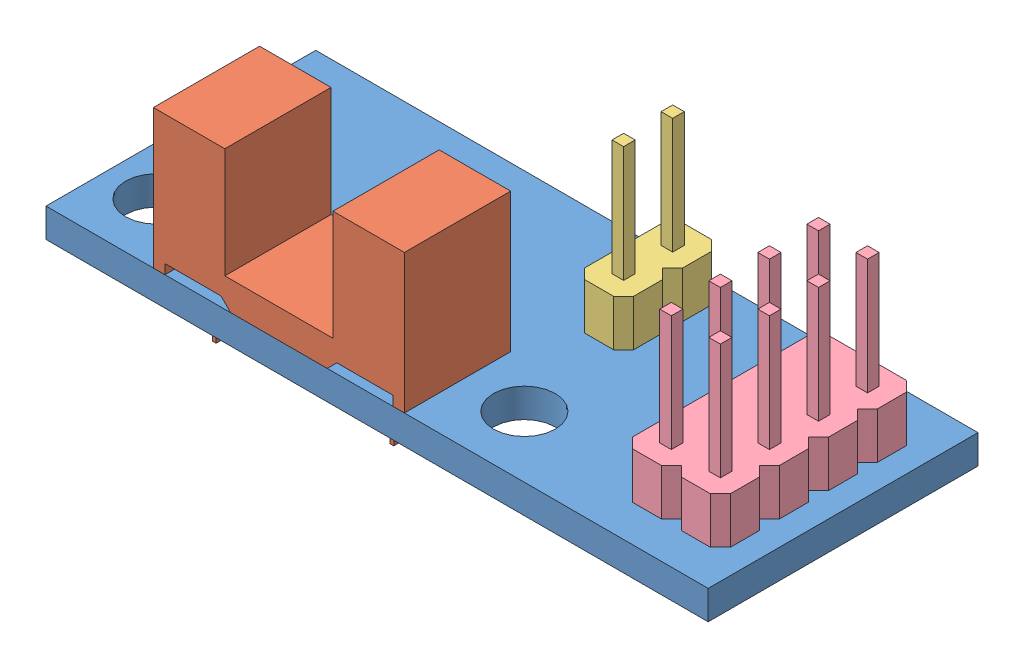
SolidWorks assembly Optoswitch board assy, configuration По умолчанию. Lengths in mm.
Overall size (34.29 11.5 13.97).
4 component instances, 4 part files, 11 mates.
Components (placement in the parent):
- Optoswitch board-1: Optoswitch board [По умолчанию] at (-0.4597 -1.5873 0) size (34.29 1.5 13.97)
- optoswitch-1: optoswitch [По умолчанию] at (-5.5447 -0.0873 1.485) size (13 10.2 5.5)
- Pin header - 2 pin-1: Pin header - 2 pin [По умолчанию] at (2.7853 -0.0873 -5.075) x (0 0 1) z (-1 0 0) size (5.08 11.5 2.54)
- Pin header - 8 pin-1: Pin header - 8 pin [По умолчанию] at (12.8753 -0.0873 0.005) x (1 0 0) z (0 1 0) size (5.08 10.16 11.5)
Mates (geometry in assembly coordinates):
- Совпадение1: coincident aligned: plane of Pin header - 2 pin-1 through (2.7853 -0.0873 -8.3641) normal (0 -1 0); plane of Pin header - 8 pin-1 through (12.8753 -0.0873 8.9818) normal (0 -1 0)
- Совпадение2: coincident aligned: plane of optoswitch-1 through (-3.0447 -0.0873 6.985) normal (0 -1 0); plane of Pin header - 2 pin-1 through (2.7853 -0.0873 -8.3641) normal (0 -1 0)
- Совпадение3: coincident anti-aligned: plane of Optoswitch board-1 through (-17.6047 -0.0873 -6.985) normal (0 1 0); plane of Pin header - 2 pin-1 through (2.7853 -0.0873 -8.3641) normal (0 -1 0)
- Параллельность1: parallel aligned: plane of Optoswitch board-1 through (16.6853 -0.0873 6.985) normal (1 0 0); plane of Pin header - 2 pin-1 through (4.0553 2.3127 -8.3641) normal (1 0 0)
- Перпендикулярность1: perpendicular: plane of Optoswitch board-1 through (16.6853 -0.0873 6.985) normal (1 0 0); plane of optoswitch-1 through (-2.7447 7.1127 1.485) normal (0 0 -1)
- Расстояние3: distance = 6.99 mm: line of Pin header - 8 pin-1 through (12.3553 2.3127 0.005) axis (0 -1 0); plane of Optoswitch board-1 through (16.6853 -0.0873 -6.985) normal (0 0 -1)
- Расстояние4: distance = 3.81 mm: line of Pin header - 8 pin-1 through (12.8753 2.3127 -0.515) axis (0 -1 0); plane of Optoswitch board-1 through (16.6853 -0.0873 6.985) normal (1 0 0)
- Расстояние5: distance = 5.56 mm aligned: plane of optoswitch-1 through (-12.0447 -0.0873 6.985) normal (-1 0 0); plane of Optoswitch board-1 through (-17.6047 -0.0873 6.985) normal (-1 0 0)
- Совпадение10: coincident aligned: plane of Optoswitch board-1 through (16.6853 -0.0873 6.985) normal (0 0 1); plane of optoswitch-1 through (-2.7447 7.1127 6.985) normal (0 0 1)
- Расстояние7: distance = 19.12 mm aligned: plane of Pin header - 2 pin-1 through (1.5153 2.3127 -8.3641) normal (-1 0 0); plane of Optoswitch board-1 through (-17.6047 -0.0873 6.985) normal (-1 0 0)
- Расстояние8: distance = 3.18 mm: line of Pin header - 2 pin-1 through (3.5353 2.3127 -3.805) axis (0 -1 0); plane of Optoswitch board-1 through (16.6853 -0.0873 -6.985) normal (0 0 -1)
